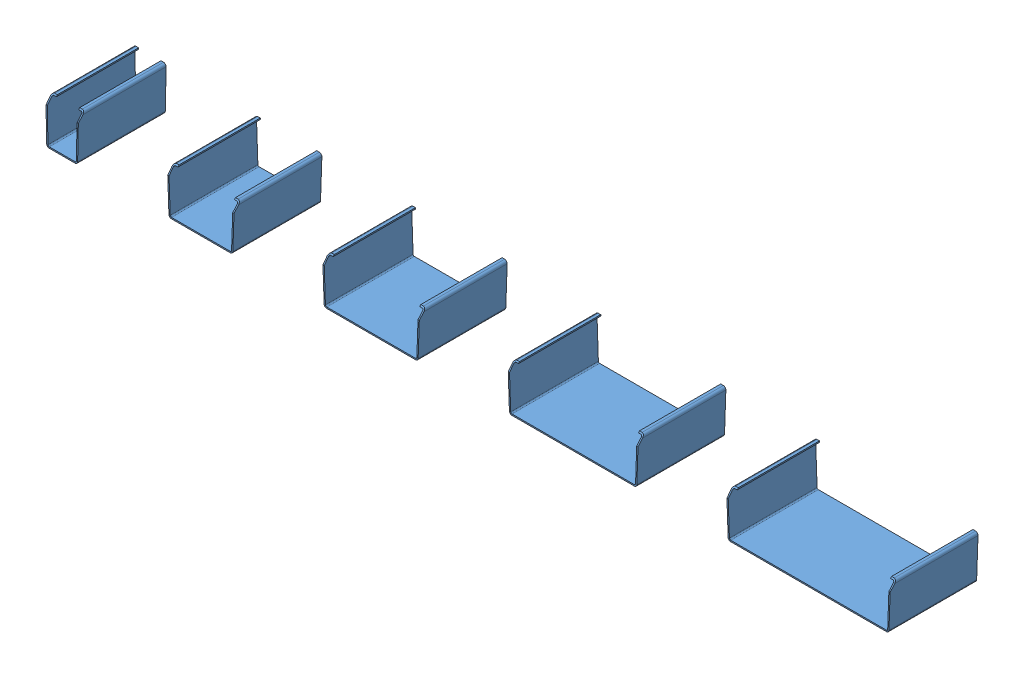
SolidWorks assembly solidworksAssembly2013SP2, configuration Default. Lengths in mm.
Overall size (656.9 34.3 68.2).
5 component instances, 1 part files, 5 mates.
Components (placement in the parent):
- solidworksPart2013SP2-1: solidworksPart2013SP2 [Default] at origin size (127.25 34.3 68.2)
- solidworksPart2013SP2-2: solidworksPart2013SP2 [Config2] at (-183.137 0 0) size (101.24 34.3 68.2)
- solidworksPart2013SP2-3: solidworksPart2013SP2 [Config1] at (-340.2739 0 0) size (75.25 34.3 68.2)
- solidworksPart2013SP2-4: solidworksPart2013SP2 [Config3] at (-472.711 0 0) size (51.85 34.3 68.2)
- solidworksPart2013SP2-5: solidworksPart2013SP2 [Config4] at (-580.62 0 0) size (25.32 34.3 68.2)
Mates (geometry in assembly coordinates):
- Coincident5: coincident aligned: plane of solidworksPart2013SP2-1 through (0 1 34.1) normal (0 1 0); plane of solidworksPart2013SP2-2 through (-183.137 1 34.1) normal (0 1 0)
- Coincident6: coincident aligned: plane of solidworksPart2013SP2-1 through (-60.5686 2 34.1) normal (0 0 1); plane of solidworksPart2013SP2-2 through (-230.7054 2 34.1) normal (0 0 1)
- Coincident8: coincident aligned: plane of solidworksPart2013SP2-2 through (-183.137 1 34.1) normal (0 1 0); plane of solidworksPart2013SP2-3 through (-340.2739 1 34.1) normal (0 1 0)
- Coincident12: coincident aligned: plane of solidworksPart2013SP2-3 through (-340.2739 1 34.1) normal (0 1 0); plane of solidworksPart2013SP2-4 through (-472.711 1 34.1) normal (0 1 0)
- Coincident15: coincident aligned: plane of solidworksPart2013SP2-4 through (-472.711 1 34.1) normal (0 1 0); plane of solidworksPart2013SP2-5 through (-580.62 1 34.1) normal (0 1 0)
